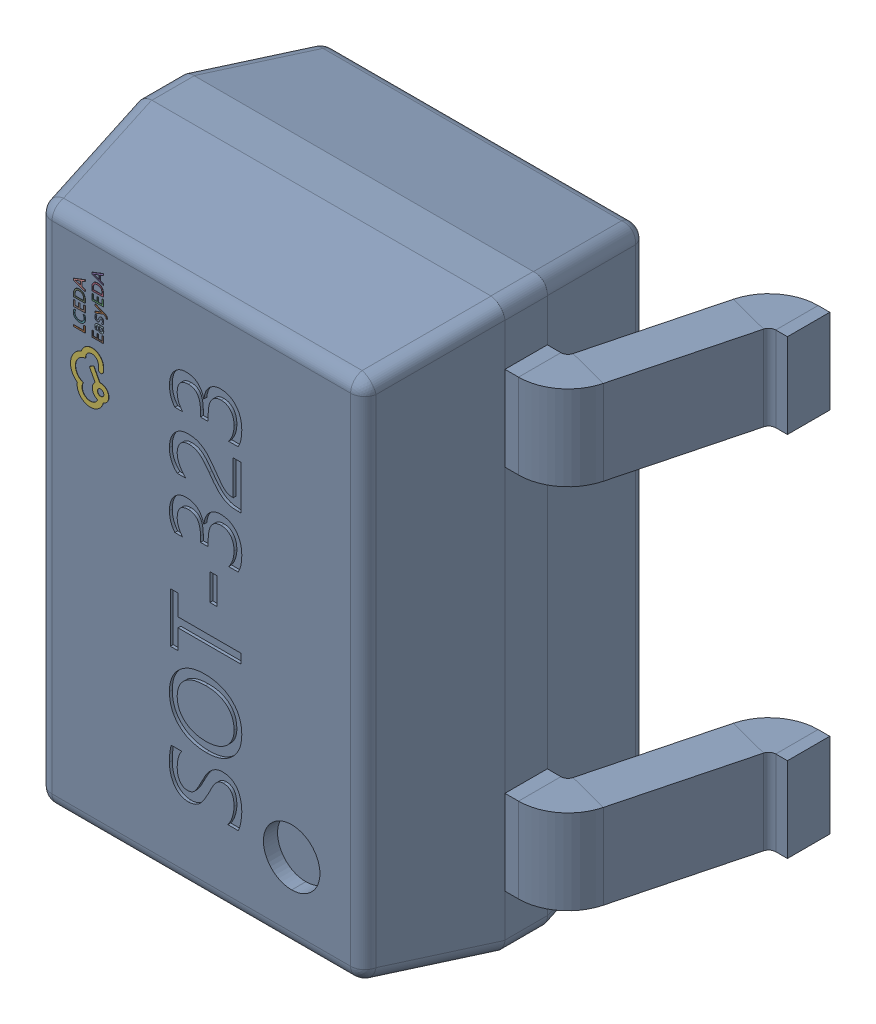
SolidWorks assembly SOT-323, configuration Défaut. Lengths in mm.
Overall size (2.1 2 1.18).
3 component instances, 1 part files, 0 mates.
Components (placement in the parent):
- D1.step-1: D1.step [Défaut] at (5.0775 -6.7805 1.6001) size (2.1 2 1.18)
  - SOT-323_L2.0-W1.3-P1.30-LS2.1-BR.step-1: SOT-323_L2.0-W1.3-P1.30-LS2.1-BR.step [Défaut] at origin size (2.1 2 1.18)
    - COMPOUND.step_247-1: COMPOUND.step_247 [Défaut] at origin size (2.1 2 1.18)
